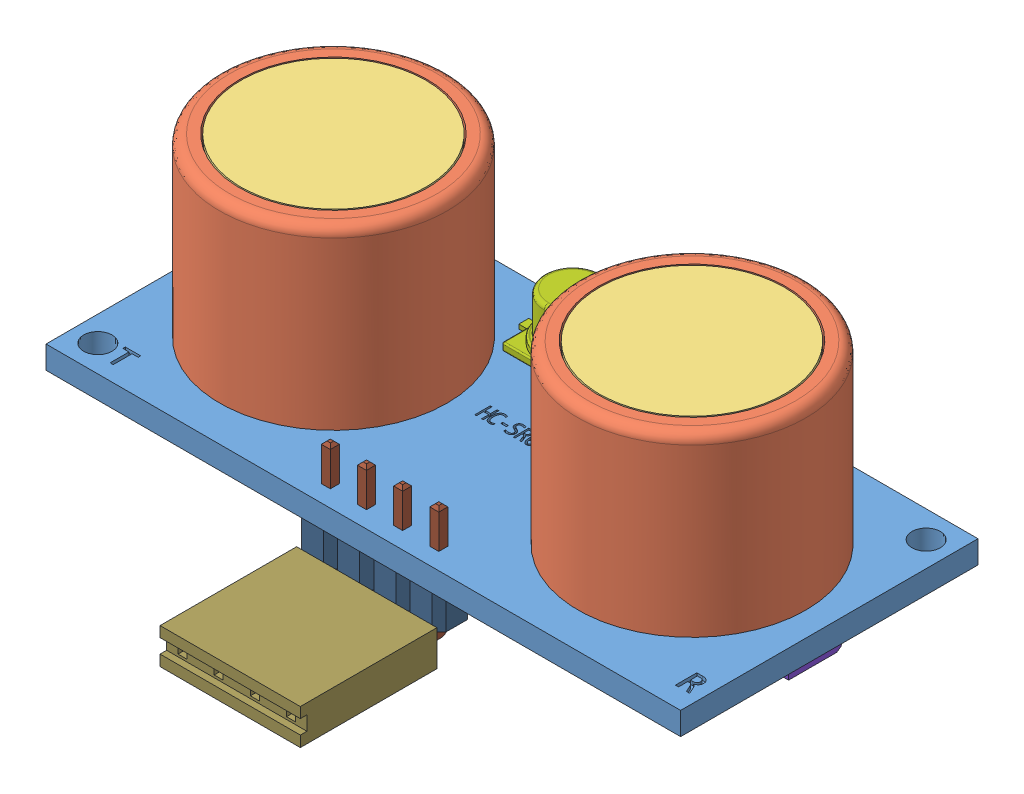
SolidWorks assembly Ultraconico, configuration Predeterminado. Lengths in mm.
Overall size (44.6 18.67 30.26).
53 component instances, 12 part files, 130 mates.
Components (placement in the parent):
- PCB-1: PCB [Predeterminado] at (-26.5389 0.8067 34.15) size (44.6 1.6 20.9)
- E&T-1: E&T [Predeterminado] at (-16.8389 14.8067 44.55) x (1 0 0) z (0 -1 0) size (16 16 12.4)
- malla-1: malla [Predeterminado] at (-16.8389 14.5067 44.55) size (13 0.3 13)
- E&T-2: E&T [Predeterminado] at (8.3611 14.8067 44.55) x (1 0 0) z (0 -1 0) size (16 16 12.4)
- malla-2: malla [Predeterminado] at (8.3611 14.5067 44.55) x (0.999998 0 -0.002228) z (0.002228 0 0.999998) size (13 0.3 13)
- 0402c_2320560-1: 0402c_2320560 [Default] at (-0.5139 0.8067 39.9) x (1 0 0) z (0 -1 0) size (1.15 0.6 0.55)
- 0404_r_1620019-1: 0404_r_1620019 [Default] at (13.5911 0.8067 50.275) x (1 0 0) z (0 -1 0) size (1.08 1.55 0.45)
- User Library-SC70-5-1-1: User Library-SC70-5-1 [Default] at (-19.3317 0.8567 36.1092) x (0 0 -1) z (0 -1 0) size (2 2.1 0.95)
- User Library-ABLS2-1: User Library-ABLS2 [Default] at (-4.1889 2.4067 37.175) x (0 0 1) z (0 1 0) size (4.85 13.3 4)
- User Library-SOIC14-150-1-1: User Library-SOIC14-150-1 [Default] at (13.4916 1.1567 44.6252) x (1 0 0) z (0 -1 0) size (8.53 5.8 1.75)
- User Library-SOIC14-150-1-2: User Library-SOIC14-150-1 [Default] at (-6.0393 1.1567 44.599) x (1 0 0) z (0 -1 0) size (8.53 5.8 1.75)
- User Library-SOIC14-150-1-3: User Library-SOIC14-150-1 [Default] at (-22.9926 1.1567 44.18) x (0 0 -1) z (0 -1 0) size (8.53 5.8 1.75)
- 0402c_2320560-2: 0402c_2320560 [Default] at (-0.5139 0.8067 37.4) x (1 0 0) z (0 -1 0) size (1.15 0.6 0.55)
- User Library-SC70-5-1-2: User Library-SC70-5-1 [Default] at (5.8054 0.8067 36.1048) x (0 0 -1) z (0 -1 0) size (2 2.1 0.95)
- 0402c_2320560-3: 0402c_2320560 [Default] at (0.4861 0.8067 41.8) x (1 0 0) z (0 -1 0) size (1.15 0.6 0.55)
- 0404_r_1620019-2: 0404_r_1620019 [Default] at (15.5711 0.8067 50.275) x (1 0 0) z (0 -1 0) size (1.08 1.55 0.45)
- 0402c_2320560-4: 0402c_2320560 [Default] at (0.4861 0.8067 45.3) x (1 0 0) z (0 -1 0) size (1.15 0.6 0.55)
- 0402c_2320560-5: 0402c_2320560 [Default] at (0.4861 0.8067 48.8) x (1 0 0) z (0 -1 0) size (1.15 0.6 0.55)
- 0404_r_1620019-3: 0404_r_1620019 [Default] at (9.6311 0.8067 50.275) x (1 0 0) z (0 -1 0) size (1.08 1.55 0.45)
- 0404_r_1620019-4: 0404_r_1620019 [Default] at (5.0711 0.8067 44.725) x (1 0 0) z (0 -1 0) size (1.08 1.55 0.45)
- 0404_r_1620019-5: 0404_r_1620019 [Default] at (5.0711 0.8067 41.175) x (1 0 0) z (0 -1 0) size (1.08 1.55 0.45)
- 0404_r_1620019-6: 0404_r_1620019 [Default] at (7.6511 0.8067 50.275) x (1 0 0) z (0 -1 0) size (1.08 1.55 0.45)
- 0404_r_1620019-7: 0404_r_1620019 [Default] at (8.6111 0.8067 39.925) x (1 0 0) z (0 -1 0) size (1.08 1.55 0.45)
- 0404_r_1620019-8: 0404_r_1620019 [Default] at (11.5911 0.8067 39.925) x (1 0 0) z (0 -1 0) size (1.08 1.55 0.45)
- 0404_r_1620019-9: 0404_r_1620019 [Default] at (14.5711 0.8067 39.925) x (1 0 0) z (0 -1 0) size (1.08 1.55 0.45)
- 0404_r_1620019-10: 0404_r_1620019 [Default] at (5.6711 0.8067 50.275) x (1 0 0) z (0 -1 0) size (1.08 1.55 0.45)
- 0404_r_1620019-11: 0404_r_1620019 [Default] at (5.0711 0.8067 48.275) x (1 0 0) z (0 -1 0) size (1.08 1.55 0.45)
- 0404_r_1620019-12: 0404_r_1620019 [Default] at (11.6111 0.8067 50.275) x (1 0 0) z (0 -1 0) size (1.08 1.55 0.45)
- 0404_r_1620019-13: 0404_r_1620019 [Default] at (-8.4089 0.8067 38.425) x (1 0 0) z (0 -1 0) size (1.08 1.55 0.45)
- 0404_r_1620019-14: 0404_r_1620019 [Default] at (-15.2639 0.8067 37.64) x (0 0 1) z (0 -1 0) size (1.08 1.55 0.45)
- 0404_r_1620019-15: 0404_r_1620019 [Default] at (-4.4289 0.8067 38.425) x (1 0 0) z (0 -1 0) size (1.08 1.55 0.45)
- 0404_r_1620019-16: 0404_r_1620019 [Default] at (-13.4075 0.8067 44.275) x (1 0 0) z (0 -1 0) size (1.08 1.55 0.45)
- 0404_r_1620019-17: 0404_r_1620019 [Default] at (-10.0589 0.8067 49.275) x (1 0 0) z (0 -1 0) size (1.08 1.55 0.45)
- 0404_r_1620019-18: 0404_r_1620019 [Default] at (-6.5789 0.8067 49.275) x (1 0 0) z (0 -1 0) size (1.08 1.55 0.45)
- 0404_r_1620019-19: 0404_r_1620019 [Default] at (-23.0489 0.8067 50.992) x (1 0 0) z (0 -1 0) size (1.08 1.55 0.45)
- 0402r_1430758-1: 0402r_1430758 [Default] at (-17.0807 0.8067 41.925) x (1 0 0) z (0 -1 0) size (1.15 0.55 0.4)
- 0402r_1430758-2: 0402r_1430758 [Default] at (-17.0807 0.8067 44.375) x (1 0 0) z (0 -1 0) size (1.15 0.55 0.4)
- 0402r_1430758-3: 0402r_1430758 [Default] at (-17.0807 0.8067 46.825) x (1 0 0) z (0 -1 0) size (1.15 0.55 0.4)
- 0404_r_1620019-20: 0404_r_1620019 [Default] at (-24.5489 0.8067 38.425) x (1 0 0) z (0 -1 0) size (1.08 1.55 0.45)
- 0404_r_1620019-21: 0404_r_1620019 [Default] at (-21.5689 0.8067 38.425) x (1 0 0) z (0 -1 0) size (1.08 1.55 0.45)
- HeaderMale-1: HeaderMale [Predeterminado] at (-7.8807 -3.0933 53.6539) x (1 0 0) z (0 1 0) size (2.54 8.73 7.94)
  - pinB-1: pinB [Predeterminado] at (-1.4403 1.348 1.3) size (2.54 2.5 2.6)
  - pinA-1: pinA [Predeterminado] at (-0.4878 -7.384 0.1595) size (0.64 7.8 7.94)
- HeaderMale-2: HeaderMale [Predeterminado] at (-0.2577 -3.0933 53.6539) x (1 0 0) z (0 1 0) size (2.54 8.73 7.94)
  - pinB-1: pinB [Predeterminado] at (-1.4403 1.348 1.3) size (2.54 2.5 2.6)
  - pinA-1: pinA [Predeterminado] at (-0.4878 -7.384 0.1595) size (0.64 7.8 7.94)
- HeaderMale-3: HeaderMale [Predeterminado] at (-2.7987 -3.0933 53.6539) x (1 0 0) z (0 1 0) size (2.54 8.73 7.94)
  - pinB-1: pinB [Predeterminado] at (-1.4403 1.348 1.3) size (2.54 2.5 2.6)
  - pinA-1: pinA [Predeterminado] at (-0.4878 -7.384 0.1595) size (0.64 7.8 7.94)
- HeaderMale-4: HeaderMale [Predeterminado] at (-5.3397 -3.0933 53.6539) x (1 0 0) z (0 1 0) size (2.54 8.73 7.94)
  - pinB-1: pinB [Predeterminado] at (-1.4403 1.348 1.3) size (2.54 2.5 2.6)
  - pinA-1: pinA [Predeterminado] at (-0.4878 -7.384 0.1595) size (0.64 7.8 7.94)
- HeaderFemale-1: HeaderFemale [Predeterminado] at (0.6906 -1.3658 64.4058) x (-1 0 0) z (0 -1 0) size (9.86 9.6 2.5)
Mates (geometry in assembly coordinates):
- Coincidente1: coincident anti-aligned: plane of PCB-1 through (-26.5389 2.4067 34.15) normal (0 1 0); plane of E&T-1 through (-16.8389 2.4067 44.55) normal (0 -1 0)
- Concéntrica1: concentric anti-aligned: cylinder of E&T-1 through (-16.8389 2.4067 44.55) axis (0 1 0) radius 6.6; cylinder of malla-1 through (-16.8389 14.8067 44.55) axis (0 -1 0) radius 6.5
- Coincidente2: coincident anti-aligned: circle of E&T-1; plane of malla-1 through (-16.8389 14.8067 44.55) normal (0 1 0)
- Coincidente3: coincident anti-aligned: plane of PCB-1 through (-26.5389 2.4067 34.15) normal (0 1 0); plane of E&T-2 through (8.3611 2.4067 44.55) normal (0 -1 0)
- Concéntrica3: concentric anti-aligned: cylinder of E&T-2 through (8.3611 2.4067 44.55) axis (0 1 0) radius 6.6; cylinder of malla-2 through (8.3611 14.8067 44.55) axis (0 -1 0) radius 6.5
- Coincidente4: coincident anti-aligned: circle of E&T-2; plane of malla-2 through (8.3611 14.8067 44.55) normal (0 1 0)
- Distancia2: distance = 1.7 mm: cylinder of E&T-1 through (-16.8389 2.4067 44.55) axis (0 1 0) radius 8; line of PCB-1 through (-26.5389 2.4067 34.15) axis (0 0 1)
- Distancia3: distance = 1.7 mm: cylinder of E&T-2 through (8.3611 2.4067 44.55) axis (0 1 0) radius 8; line of PCB-1 through (18.0611 2.4067 55.05) axis (0 0 -1)
- Distancia4: distance = 2.5 mm: cylinder of E&T-1 through (-16.8389 2.4067 44.55) axis (0 1 0) radius 8; line of PCB-1 through (-26.5389 2.4067 55.05) axis (1 0 0)
- Distancia5: distance = 2.5 mm: cylinder of E&T-2 through (8.3611 2.4067 44.55) axis (0 1 0) radius 8; line of PCB-1 through (-26.5389 2.4067 55.05) axis (1 0 0)
- Coincidente12: coincident anti-aligned: plane of PCB-1 through (-26.5389 0.8067 34.15) normal (0 -1 0); plane of User Library-SC70-5-1-1 through (-18.7067 0.8067 35.1092) normal (0 1 0)
- Coincidente13: coincident anti-aligned: plane of PCB-1 through (-26.5389 0.8067 34.15) normal (0 -1 0); plane of 0404_r_1620019-1 through (13.0511 0.8067 49.5) normal (0 1 0)
- Coincidente14: coincident anti-aligned: plane of PCB-1 through (-26.5389 0.8067 34.15) normal (0 -1 0); plane of 0402c_2320560-1 through (-0.5139 0.8067 40.75) normal (0 1 0)
- Coincidente15: coincident anti-aligned: plane of PCB-1 through (-26.5389 2.4067 34.15) normal (0 1 0); plane of User Library-ABLS2-1 through (2.4611 2.4067 37.525) normal (0 -1 0)
- Coincidente16: coincident anti-aligned: plane of PCB-1 through (-26.5389 0.8067 34.15) normal (0 -1 0); plane of User Library-SOIC14-150-1-1 through (18.3916 0.8067 42.7252) normal (0 1 0)
- Distancia6: distance = 0.6 mm aligned: plane of User Library-ABLS2-1 through (-9.9389 2.5567 34.75) normal (0 0 -1); plane of PCB-1 through (-26.5389 2.4067 34.15) normal (0 0 -1)
- Distancia7: distance = 16.5 mm aligned: plane of PCB-1 through (18.0611 2.4067 34.15) normal (1 0 0); plane of User Library-ABLS2-1 through (1.5611 2.5567 39.6) normal (1 0 0)
- Coincidente19: coincident anti-aligned: plane of PCB-1 through (-26.5389 0.8067 34.15) normal (0 -1 0); plane of User Library-SOIC14-150-1-3 through (-24.8926 0.8067 39.28) normal (0 1 0)
- Coincidente20: coincident anti-aligned: plane of PCB-1 through (-26.5389 0.8067 34.15) normal (0 -1 0); plane of User Library-SOIC14-150-1-2 through (-1.1393 0.8067 42.699) normal (0 1 0)
- Distancia8: distance = 1.0453 mm: line of User Library-SOIC14-150-1-1 through (17.0158 0.8067 46.4621) axis (0 0 -1); plane of PCB-1 through (18.0611 2.4067 34.15) normal (1 0 0)
- Distancia9: distance = 8.5879 mm: line of User Library-SOIC14-150-1-1 through (8.6546 0.8067 46.4621) axis (1 0 0); plane of PCB-1 through (18.0611 2.4067 55.05) normal (0 0 1)
- Distancia10: distance = 11 mm: plane of User Library-SOIC14-150-1-2 through (-2.4093 0.2067 41.699) normal (0.984808 0.173648 0); line of User Library-SOIC14-150-1-1 through (8.6546 0.8067 42.7883) axis (0 0 1)
- Distancia11: distance = 8.5669 mm: plane of User Library-SOIC14-150-1-2 through (-1.1393 0.8067 46.4359) normal (0 0.104528 0.994522); line of PCB-1 through (-26.5389 0.8067 55.05) axis (1 0 0)
- Distancia12: distance = 1.7 mm: plane of User Library-SOIC14-150-1-3 through (-24.8296 0.8067 39.28) normal (-0.994522 0.104528 0); line of PCB-1 through (-26.5389 0.8067 34.15) axis (0 0 1)
- Distancia13: distance = 6 mm: plane of User Library-SOIC14-150-1-3 through (-24.8926 0.8067 49.017) normal (0 0.104528 0.994522); line of PCB-1 through (-26.5389 0.8067 55.05) axis (1 0 0)
- Coincidente27: coincident anti-aligned: plane of PCB-1 through (-26.5389 0.8067 34.15) normal (0 -1 0); plane of User Library-SC70-5-1-2 through (6.6554 0.8067 36.6423) normal (0 1 0)
- Coincidente28: coincident anti-aligned: plane of PCB-1 through (-26.5389 0.8067 34.15) normal (0 -1 0); plane of 0402c_2320560-2 through (-0.5139 0.8067 38.25) normal (0 1 0)
- Coincidente29: coincident anti-aligned: plane of PCB-1 through (-26.5389 0.8067 34.15) normal (0 -1 0); plane of 0402c_2320560-3 through (0.4861 0.8067 42.65) normal (0 1 0)
- Coincidente30: coincident anti-aligned: plane of PCB-1 through (-26.5389 0.8067 34.15) normal (0 -1 0); plane of 0402c_2320560-4 through (0.4861 0.8067 46.15) normal (0 1 0)
- Coincidente31: coincident anti-aligned: plane of PCB-1 through (-26.5389 0.8067 34.15) normal (0 -1 0); plane of 0402c_2320560-5 through (0.4861 0.8067 49.65) normal (0 1 0)
- Coincidente32: coincident anti-aligned: plane of PCB-1 through (-26.5389 0.8067 34.15) normal (0 -1 0); plane of 0404_r_1620019-2 through (15.0311 0.8067 49.5) normal (0 1 0)
- Distancia14: distance = 11.6352 mm: line of PCB-1 through (18.0611 0.8067 55.05) axis (0 0 -1); plane of User Library-SC70-5-1-2 through (6.4304 0.2467 37.1048) normal (0.996195 0.087156 0)
- Distancia15: distance = 1 mm: plane of User Library-SC70-5-1-2 through (5.1804 0.2467 35.1048) normal (0 0.087156 -0.996195); line of PCB-1 through (18.0611 0.8067 34.15) axis (-1 0 0)
- Distancia16: distance = 6.6017 mm: plane of User Library-SC70-5-1-1 through (-19.9567 0.2967 37.1092) normal (-0.996195 0.087156 0); line of PCB-1 through (-26.5389 0.8067 34.15) axis (0 0 1)
- Distancia17: distance = 1 mm: plane of User Library-SC70-5-1-1 through (-19.9567 0.2967 35.1092) normal (0 0.087156 -0.996195); line of PCB-1 through (18.0611 0.8067 34.15) axis (-1 0 0)
- Coincidente37: coincident anti-aligned: plane of PCB-1 through (-26.5389 0.8067 34.15) normal (0 -1 0); plane of 0404_r_1620019-9 through (14.0311 0.8067 39.15) normal (0 1 0)
- Coincidente38: coincident anti-aligned: plane of PCB-1 through (-26.5389 0.8067 34.15) normal (0 -1 0); plane of 0404_r_1620019-8 through (11.0511 0.8067 39.15) normal (0 1 0)
- Coincidente39: coincident anti-aligned: plane of PCB-1 through (-26.5389 0.8067 34.15) normal (0 -1 0); plane of 0404_r_1620019-7 through (8.0711 0.8067 39.15) normal (0 1 0)
- Coincidente40: coincident anti-aligned: plane of PCB-1 through (-26.5389 0.8067 34.15) normal (0 -1 0); plane of 0404_r_1620019-10 through (5.1311 0.8067 49.5) normal (0 1 0)
- Coincidente41: coincident anti-aligned: plane of PCB-1 through (-26.5389 0.8067 34.15) normal (0 -1 0); plane of 0404_r_1620019-6 through (7.1111 0.8067 49.5) normal (0 1 0)
- Coincidente42: coincident anti-aligned: plane of PCB-1 through (-26.5389 0.8067 34.15) normal (0 -1 0); plane of 0404_r_1620019-5 through (4.5311 0.8067 40.4) normal (0 1 0)
- Coincidente43: coincident anti-aligned: plane of PCB-1 through (-26.5389 0.8067 34.15) normal (0 -1 0); plane of 0404_r_1620019-4 through (4.5311 0.8067 43.95) normal (0 1 0)
- Coincidente44: coincident anti-aligned: plane of PCB-1 through (-26.5389 0.8067 34.15) normal (0 -1 0); plane of 0404_r_1620019-11 through (4.5311 0.8067 47.5) normal (0 1 0)
- Coincidente45: coincident anti-aligned: plane of PCB-1 through (-26.5389 0.8067 34.15) normal (0 -1 0); plane of 0404_r_1620019-3 through (9.0911 0.8067 49.5) normal (0 1 0)
- Coincidente46: coincident anti-aligned: plane of PCB-1 through (-26.5389 0.8067 34.15) normal (0 -1 0); plane of 0404_r_1620019-12 through (11.0711 0.8067 49.5) normal (0 1 0)
- Coincidente47: coincident anti-aligned: plane of PCB-1 through (-26.5389 0.8067 34.15) normal (0 -1 0); plane of 0404_r_1620019-15 through (-4.9689 0.8067 37.65) normal (0 1 0)
- Coincidente48: coincident anti-aligned: plane of PCB-1 through (-26.5389 0.8067 34.15) normal (0 -1 0); plane of 0404_r_1620019-13 through (-8.9489 0.8067 37.65) normal (0 1 0)
- Coincidente49: coincident anti-aligned: plane of PCB-1 through (-26.5389 0.8067 34.15) normal (0 -1 0); plane of 0404_r_1620019-14 through (-14.4889 0.8067 37.1) normal (0 1 0)
- Coincidente50: coincident anti-aligned: plane of PCB-1 through (-26.5389 0.8067 34.15) normal (0 -1 0); plane of 0404_r_1620019-16 through (-13.9475 0.8067 43.5) normal (0 1 0)
- Coincidente51: coincident anti-aligned: plane of PCB-1 through (-26.5389 0.8067 34.15) normal (0 -1 0); plane of 0404_r_1620019-17 through (-10.5989 0.8067 48.5) normal (0 1 0)
- Coincidente52: coincident anti-aligned: plane of PCB-1 through (-26.5389 0.8067 34.15) normal (0 -1 0); plane of 0404_r_1620019-18 through (-7.1189 0.8067 48.5) normal (0 1 0)
- Coincidente53: coincident anti-aligned: plane of PCB-1 through (-26.5389 0.8067 34.15) normal (0 -1 0); plane of 0404_r_1620019-19 through (-23.5889 0.8067 50.217) normal (0 1 0)
- Distancia18: distance = 2 mm: plane of 0404_r_1620019-2 through (16.0611 0.8067 49.9) normal (1 0 0); line of PCB-1 through (18.0611 0.8067 55.05) axis (0 0 -1)
- Distancia19: distance = 1 mm: plane of 0404_r_1620019-1 through (14.0811 0.8067 49.9) normal (1 0 0); line of 0404_r_1620019-2 through (15.0811 0.8067 49.9) axis (0 0 1)
- Distancia20: distance = 1 mm: plane of 0404_r_1620019-12 through (12.1011 0.8067 49.9) normal (1 0 0); line of 0404_r_1620019-1 through (13.1011 0.8067 49.9) axis (0 0 1)
- Distancia21: distance = 1 mm: plane of 0404_r_1620019-3 through (10.1211 0.8067 49.9) normal (1 0 0); line of 0404_r_1620019-12 through (11.1211 0.8067 49.9) axis (0 0 1)
- Distancia22: distance = 12.5 mm: plane of 0404_r_1620019-11 through (5.5611 0.8067 47.9) normal (1 0 0); line of PCB-1 through (18.0611 0.8067 55.05) axis (0 0 -1)
- Distancia23: distance = 12.5 mm: plane of 0404_r_1620019-4 through (5.5611 0.8067 44.35) normal (1 0 0); line of PCB-1 through (18.0611 0.8067 55.05) axis (0 0 -1)
- Distancia24: distance = 12.5 mm: plane of 0404_r_1620019-5 through (5.5611 0.8067 40.8) normal (1 0 0); line of PCB-1 through (18.0611 0.8067 55.05) axis (0 0 -1)
- Distancia25: distance = 1 mm: plane of 0404_r_1620019-6 through (8.1411 0.8067 49.9) normal (1 0 0); line of 0404_r_1620019-3 through (9.1411 0.8067 49.9) axis (0 0 1)
- Distancia26: distance = 1 mm: plane of 0404_r_1620019-10 through (6.1611 0.8067 49.9) normal (1 0 0); line of 0404_r_1620019-6 through (7.1611 0.8067 49.9) axis (0 0 1)
- Distancia27: distance = 3 mm: plane of 0404_r_1620019-9 through (15.0611 0.8067 39.55) normal (1 0 0); line of PCB-1 through (18.0611 0.8067 55.05) axis (0 0 -1)
- Distancia28: distance = 2 mm: plane of 0404_r_1620019-8 through (12.0811 0.8067 39.55) normal (1 0 0); line of 0404_r_1620019-9 through (14.0811 0.8067 39.55) axis (0 0 1)
- Distancia29: distance = 2 mm: plane of 0404_r_1620019-7 through (9.1011 0.8067 39.55) normal (1 0 0); line of 0404_r_1620019-8 through (11.1011 0.8067 39.55) axis (0 0 1)
- Distancia30: distance = 17 mm: line of 0402c_2320560-3 through (1.0611 0.8067 41.525) axis (0 0 1); line of PCB-1 through (18.0611 0.8067 55.05) axis (0 0 -1)
- Distancia31: distance = 17 mm: line of 0402c_2320560-4 through (1.0611 0.8067 45.025) axis (0 0 1); plane of PCB-1 through (18.0611 2.4067 34.15) normal (1 0 0)
- Distancia32: distance = 17 mm: plane of 0402c_2320560-5 through (1.0611 0.2567 48.525) normal (1 0 0); line of PCB-1 through (18.0611 0.8067 55.05) axis (0 0 -1)
- Distancia33: distance = 18 mm: plane of 0402c_2320560-1 through (0.0611 0.2567 39.625) normal (1 0 0); line of PCB-1 through (18.0611 0.8067 55.05) axis (0 0 -1)
- Distancia34: distance = 18 mm: plane of 0402c_2320560-2 through (0.0611 0.2567 37.125) normal (1 0 0); line of PCB-1 through (18.0611 0.8067 55.05) axis (0 0 -1)
- Distancia35: distance = 4 mm: plane of 0404_r_1620019-2 through (16.1111 0.3567 51.05) normal (0 0 1); line of PCB-1 through (-26.5389 0.8067 55.05) axis (1 0 0)
- Distancia36: distance = 4 mm: plane of 0404_r_1620019-1 through (14.1311 0.3567 51.05) normal (0 0 1); line of PCB-1 through (-26.5389 0.8067 55.05) axis (1 0 0)
- Distancia37: distance = 4 mm: plane of 0404_r_1620019-12 through (12.1511 0.3567 51.05) normal (0 0 1); line of PCB-1 through (-26.5389 0.8067 55.05) axis (1 0 0)
- Distancia38: distance = 4 mm: plane of 0404_r_1620019-3 through (10.1711 0.3567 51.05) normal (0 0 1); line of PCB-1 through (-26.5389 0.8067 55.05) axis (1 0 0)
- Distancia39: distance = 4 mm: plane of 0404_r_1620019-6 through (8.1911 0.3567 51.05) normal (0 0 1); line of PCB-1 through (-26.5389 0.8067 55.05) axis (1 0 0)
- Distancia40: distance = 4 mm: plane of 0404_r_1620019-10 through (6.2111 0.3567 51.05) normal (0 0 1); line of PCB-1 through (-26.5389 0.8067 55.05) axis (1 0 0)
- Distancia41: distance = 6 mm: plane of 0404_r_1620019-11 through (5.6111 0.3567 49.05) normal (0 0 1); line of PCB-1 through (-26.5389 0.8067 55.05) axis (1 0 0)
- Distancia42: distance = 2 mm: plane of 0404_r_1620019-11 through (4.5311 0.3567 47.5) normal (0 0 -1); line of 0404_r_1620019-4 through (5.6111 0.8067 45.5) axis (-1 0 0)
- Distancia43: distance = 2 mm: plane of 0404_r_1620019-4 through (4.5311 0.3567 43.95) normal (0 0 -1); line of 0404_r_1620019-5 through (5.6111 0.8067 41.95) axis (-1 0 0)
- Distancia44: distance = 5 mm: plane of 0404_r_1620019-7 through (8.0711 0.3567 39.15) normal (0 0 -1); line of PCB-1 through (18.0611 0.8067 34.15) axis (-1 0 0)
- Distancia45: distance = 5 mm: plane of 0404_r_1620019-8 through (11.0511 0.3567 39.15) normal (0 0 -1); line of PCB-1 through (18.0611 0.8067 34.15) axis (-1 0 0)
- Distancia46: distance = 5 mm: plane of 0404_r_1620019-9 through (14.0311 0.3567 39.15) normal (0 0 -1); line of PCB-1 through (18.0611 0.8067 34.15) axis (-1 0 0)
- Distancia48: distance = 6 mm: plane of 0402c_2320560-5 through (0.7611 10.2567 49.05) normal (0 0 1); line of PCB-1 through (-26.5389 0.8067 55.05) axis (1 0 0)
- Distancia49: distance = 3 mm: plane of 0402c_2320560-4 through (0.7611 10.2567 45.55) normal (0 0 1); line of 0402c_2320560-5 through (0.7611 0.8067 48.55) axis (-1 0 0)
- Distancia50: distance = 3 mm: plane of 0402c_2320560-4 through (0.2111 10.2567 45.05) normal (0 0 -1); line of 0402c_2320560-3 through (0.2111 0.8067 42.05) axis (1 0 0)
- Distancia51: distance = 3 mm: plane of 0402c_2320560-2 through (-0.7889 10.2567 37.15) normal (0 0 -1); line of PCB-1 through (18.0611 0.8067 34.15) axis (-1 0 0)
- Distancia52: distance = 2 mm: plane of 0402c_2320560-1 through (-0.7889 10.2567 39.65) normal (0 0 -1); line of 0402c_2320560-2 through (-0.7889 0.8067 37.65) axis (1 0 0)
- Coincidente89: coincident anti-aligned: plane of PCB-1 through (-26.5389 0.8067 34.15) normal (0 -1 0); plane of 0402r_1430758-1 through (-17.0807 0.8067 42.75) normal (0 1 0)
- Coincidente90: coincident anti-aligned: plane of PCB-1 through (-26.5389 0.8067 34.15) normal (0 -1 0); plane of 0402r_1430758-2 through (-17.0807 0.8067 45.2) normal (0 1 0)
- Coincidente91: coincident anti-aligned: plane of PCB-1 through (-26.5389 0.8067 34.15) normal (0 -1 0); plane of 0402r_1430758-3 through (-17.0807 0.8067 47.65) normal (0 1 0)
- Coincidente92: coincident anti-aligned: plane of PCB-1 through (-26.5389 0.8067 34.15) normal (0 -1 0); plane of 0404_r_1620019-21 through (-22.1089 0.8067 37.65) normal (0 1 0)
- Coincidente93: coincident anti-aligned: plane of PCB-1 through (-26.5389 0.8067 34.15) normal (0 -1 0); plane of 0404_r_1620019-20 through (-25.0889 0.8067 37.65) normal (0 1 0)
- Distancia53: distance = 3.5 mm: plane of 0404_r_1620019-15 through (-4.9689 0.3567 37.65) normal (0 0 -1); line of PCB-1 through (18.0611 0.8067 34.15) axis (-1 0 0)
- Distancia54: distance = 3.5 mm: plane of 0404_r_1620019-13 through (-8.9489 0.3567 37.65) normal (0 0 -1); line of PCB-1 through (18.0611 0.8067 34.15) axis (-1 0 0)
- Distancia55: distance = 22 mm: plane of 0404_r_1620019-15 through (-3.9389 0.8067 38.05) normal (1 0 0); line of PCB-1 through (18.0611 0.8067 55.05) axis (0 0 -1)
- Distancia56: distance = 3 mm: plane of 0404_r_1620019-13 through (-7.9189 0.8067 38.05) normal (1 0 0); line of 0404_r_1620019-15 through (-4.9189 0.8067 38.05) axis (0 0 1)
- Distancia57: distance = 3 mm: plane of 0404_r_1620019-14 through (-15.6389 0.8067 37.15) normal (0 0 -1); line of PCB-1 through (18.0611 0.8067 34.15) axis (-1 0 0)
- Distancia58: distance = 10.5 mm: plane of 0404_r_1620019-14 through (-16.0389 0.3567 38.18) normal (-1 0 0); line of PCB-1 through (-26.5389 0.8067 34.15) axis (0 0 1)
- Distancia59: distance = 3.5 mm: plane of 0404_r_1620019-21 through (-22.1089 0.3567 37.65) normal (0 0 -1); line of PCB-1 through (18.0611 0.8067 34.15) axis (-1 0 0)
- Distancia60: distance = 3.5 mm: plane of 0404_r_1620019-20 through (-25.0889 0.3567 37.65) normal (0 0 -1); line of PCB-1 through (18.0611 0.8067 34.15) axis (-1 0 0)
- Distancia61: distance = 1.5 mm: plane of 0404_r_1620019-20 through (-25.0389 0.8067 38.8) normal (-1 0 0); line of PCB-1 through (-26.5389 0.8067 34.15) axis (0 0 1)
- Distancia62: distance = 2 mm: plane of 0404_r_1620019-21 through (-22.0589 0.8067 38.8) normal (-1 0 0); line of 0404_r_1620019-20 through (-24.0589 0.8067 38.8) axis (0 0 -1)
- Distancia63: distance = 2.0413 mm: plane of 0404_r_1620019-16 through (-12.9175 0.8067 43.9) normal (1 0 0); line of User Library-SOIC14-150-1-2 through (-10.8762 0.8067 42.762) axis (0 0 1)
- Distancia64: distance = 10 mm: line of PCB-1 through (-26.5389 0.8067 55.05) axis (1 0 0); plane of 0404_r_1620019-16 through (-12.8675 0.3567 45.05) normal (0 0 1)
- Distancia65: distance = 6 mm: plane of 0402c_2320560-5 through (-0.0889 0.2567 49.075) normal (-1 0 0); line of 0404_r_1620019-18 through (-6.0889 0.8067 49.65) axis (0 0 -1)
- Distancia66: distance = 2.5 mm: plane of 0404_r_1620019-17 through (-9.5689 0.8067 48.9) normal (1 0 0); line of 0404_r_1620019-18 through (-7.0689 0.8067 48.9) axis (0 0 1)
- Distancia67: distance = 5 mm: plane of 0404_r_1620019-17 through (-9.5189 0.3567 50.05) normal (0 0 1); line of PCB-1 through (-26.5389 0.8067 55.05) axis (1 0 0)
- Distancia68: distance = 5 mm: plane of 0404_r_1620019-18 through (-6.0389 0.3567 50.05) normal (0 0 1); line of PCB-1 through (-26.5389 0.8067 55.05) axis (1 0 0)
- Distancia69: distance = 1.2 mm: plane of 0404_r_1620019-19 through (-23.5889 0.3567 50.217) normal (0 0 -1); line of User Library-SOIC14-150-1-3 through (-24.8296 0.8067 49.017) axis (1 0 0)
- Distancia70: distance = 3 mm: plane of 0404_r_1620019-19 through (-23.5389 0.8067 51.367) normal (-1 0 0); line of PCB-1 through (-26.5389 0.8067 34.15) axis (0 0 1)
- Distancia71: distance = 8 mm: plane of 0402r_1430758-3 through (-16.8057 0.8067 47.05) normal (0 0 1); line of PCB-1 through (-26.5389 0.8067 55.05) axis (1 0 0)
- Distancia72: distance = 2 mm: plane of 0402r_1430758-2 through (-16.8057 0.8067 44.6) normal (0 0 1); line of 0402r_1430758-3 through (-16.8057 0.8067 46.6) axis (-1 0 0)
- Distancia73: distance = 2 mm: plane of 0402r_1430758-2 through (-17.3557 0.8067 44.15) normal (0 0 -1); line of 0402r_1430758-1 through (-17.3557 0.8067 42.15) axis (1 0 0)
- Distancia74: distance = 3.5 mm: plane of 0402r_1430758-1 through (-17.6557 0.4067 42.175) normal (-1 0 0); line of User Library-SOIC14-150-1-3 through (-21.1557 0.8067 49.017) axis (0 0 -1)
- Distancia75: distance = 3.5 mm: line of User Library-SOIC14-150-1-3 through (-21.1557 0.8067 49.017) axis (0 0 -1); plane of 0402r_1430758-2 through (-17.6557 0.4067 44.625) normal (-1 0 0)
- Distancia76: distance = 3.5 mm: plane of 0402r_1430758-3 through (-17.6557 0.4067 47.075) normal (-1 0 0); line of User Library-SOIC14-150-1-3 through (-21.1557 0.8067 49.017) axis (0 0 -1)
- Coincidente108: coincident anti-aligned: plane of PCB-1 through (-3.2864 -7.5933 53.2378) normal (0 0 1); plane of HeaderMale-4/pinA-1 through (-5.8274 -2.9338 53.2378) normal (0 0 -1)
- Coincidente109: coincident anti-aligned: plane of PCB-1 through (-5.1914 -7.5933 53.2378) normal (0 0 1); plane of HeaderMale-3/pinA-1 through (-3.2864 -2.9338 53.2378) normal (0 0 -1)
- Coincidente111: coincident anti-aligned: plane of PCB-1 through (-2.6504 -7.5933 53.2378) normal (-1 0 0); plane of HeaderMale-3/pinA-1 through (-2.6504 -2.9338 53.2378) normal (1 0 0)
- Coincidente112: coincident anti-aligned: plane of PCB-1 through (-5.1914 -7.5933 53.2378) normal (-1 0 0); plane of HeaderMale-4/pinA-1 through (-5.1914 -2.9338 53.2378) normal (1 0 0)
- Coincidente114: coincident anti-aligned: plane of PCB-1 through (-26.5389 0.8067 34.15) normal (0 -1 0); plane of HeaderMale-2/pinB-1 through (-1.6979 0.8067 52.3058) normal (0 1 0)
- Coincidente115: coincident anti-aligned: plane of PCB-1 through (-26.5389 0.8067 34.15) normal (0 -1 0); plane of HeaderMale-3/pinB-1 through (-4.2389 0.8067 52.3058) normal (0 1 0)
- Coincidente116: coincident anti-aligned: plane of PCB-1 through (-26.5389 0.8067 34.15) normal (0 -1 0); plane of HeaderMale-4/pinB-1 through (-6.7799 0.8067 52.3058) normal (0 1 0)
- Coincidente117: coincident anti-aligned: plane of PCB-1 through (-26.5389 0.8067 34.15) normal (0 -1 0); plane of HeaderMale-1/pinB-1 through (-9.3209 0.8067 52.3058) normal (0 1 0)
- Coincidente118: coincident anti-aligned: plane of PCB-1 through (-8.3684 -7.5933 53.2378) normal (0 0 1); plane of HeaderMale-1/pinA-1 through (-8.3684 -2.9338 53.2378) normal (0 0 -1)
- Coincidente119: coincident anti-aligned: plane of PCB-1 through (-8.3684 -7.5933 53.8738) normal (1 0 0); plane of HeaderMale-1/pinA-1 through (-8.3684 -2.9338 53.2378) normal (-1 0 0)
- Coincidente120: coincident anti-aligned: plane of PCB-1 through (-0.7454 -7.5933 53.2378) normal (1 0 0); plane of HeaderMale-2/pinA-1 through (-0.7454 -2.9338 53.2378) normal (-1 0 0)
- Coincidente121: coincident anti-aligned: plane of PCB-1 through (-0.1094 -7.5933 53.2378) normal (0 0 1); plane of HeaderMale-2/pinA-1 through (-0.7454 -2.9338 53.2378) normal (0 0 -1)
- Coincidente123: coincident anti-aligned: plane of HeaderMale-1/pinA-1 through (-8.3684 -2.9338 53.2378) normal (0 -1 0); plane of HeaderFemale-1 through (-8.3684 -2.9338 55.6954) normal (0 1 0)
- Coincidente124: coincident anti-aligned: plane of HeaderMale-1/pinA-1 through (-8.3684 -2.9338 53.2378) normal (-1 0 0); plane of HeaderFemale-1 through (-8.3684 -2.2978 55.6954) normal (1 0 0)
- Coincidente126: coincident anti-aligned: plane of HeaderMale-3/pinB-1 through (-4.2389 0.8067 54.8058) normal (0 0 1); plane of HeaderFemale-1 through (0.6906 -1.3658 54.8058) normal (0 0 -1)
